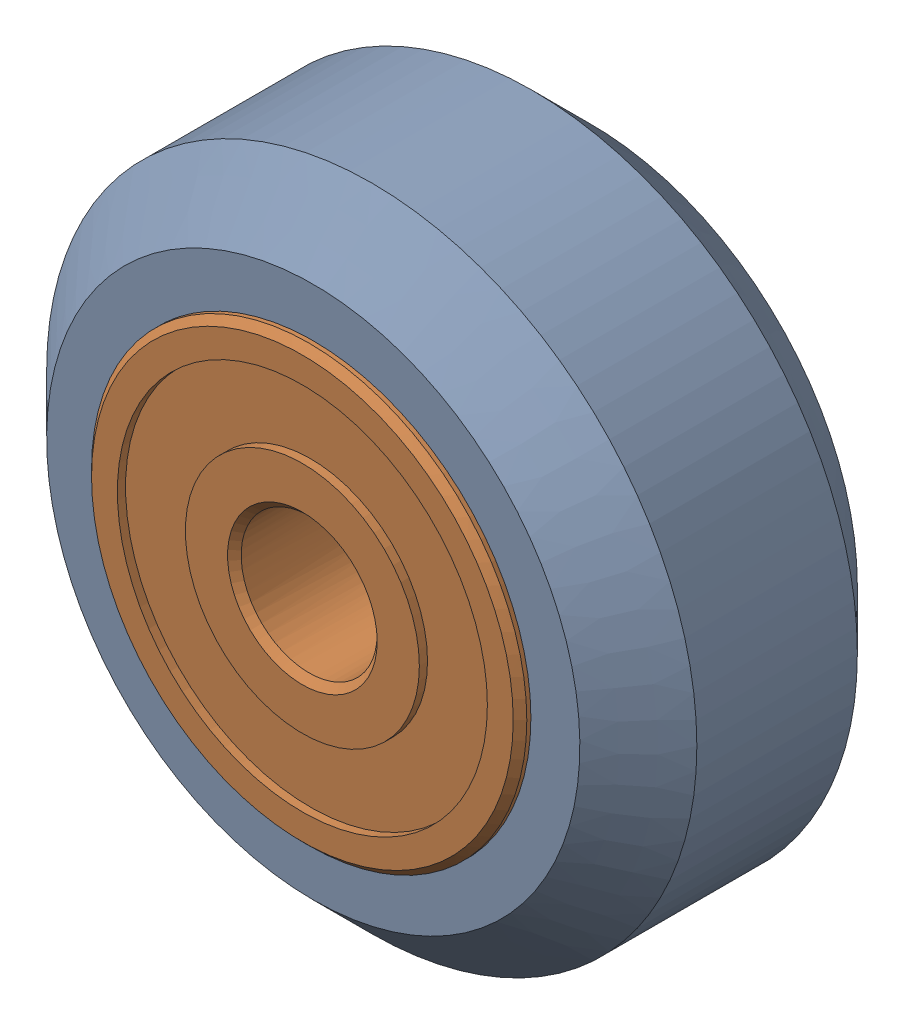
SolidWorks assembly Xtreme Solid V Wheel Assembly_7, configuration Default. Lengths in mm.
Overall size (23.9 23.9 11).
3 component instances, 2 part files, 0 mates.
Components (placement in the parent):
- Xtreme Solid V Wheel-1: Xtreme Solid V Wheel [Default] at (-115.15 -25.79 30) x (0 0 1) z (-1 0 0) size (10.2 23.9 23.9)
- Wheel+Kit+-+5x16x5mm+Sealed+Radial+Ball+Bearing.step.f3d-1: Wheel+Kit+-+5x16x5mm+Sealed+Radial+Ball+Bearing.step.f3d [Default] at (-115.15 -25.79 30) x (0 1 0) z (-1 0 0) size (16 5 16)
- Wheel+Kit+-+5x16x5mm+Sealed+Radial+Ball+Bearing.step.f3d-2: Wheel+Kit+-+5x16x5mm+Sealed+Radial+Ball+Bearing.step.f3d [Default] at (-115.15 -25.79 30) x (0 1 0) z (1 0 0) size (16 5 16)
